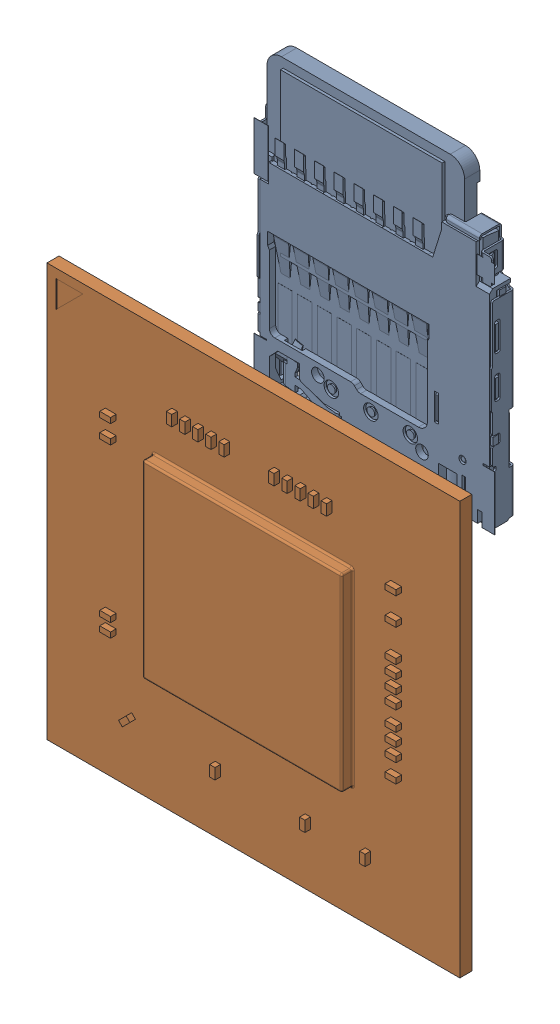
SolidWorks assembly 142-13448-1000-A02_ASM, configuration Défaut. Lengths in mm.
Overall size (23 37.02 4.04).
2 component instances, 2 part files, 0 mates.
Components (placement in the parent):
- 080-0051-000_3-1: 080-0051-000_3 [Défaut] at (28.331 29.139 0) x (-1 0 0) z (0 0 -1) size (13.4 17 1.29)
- TM670M-A2_1-1: TM670M-A2_1 [Défaut] at (23.7 13.45 1.2) size (23 23 1.31)
